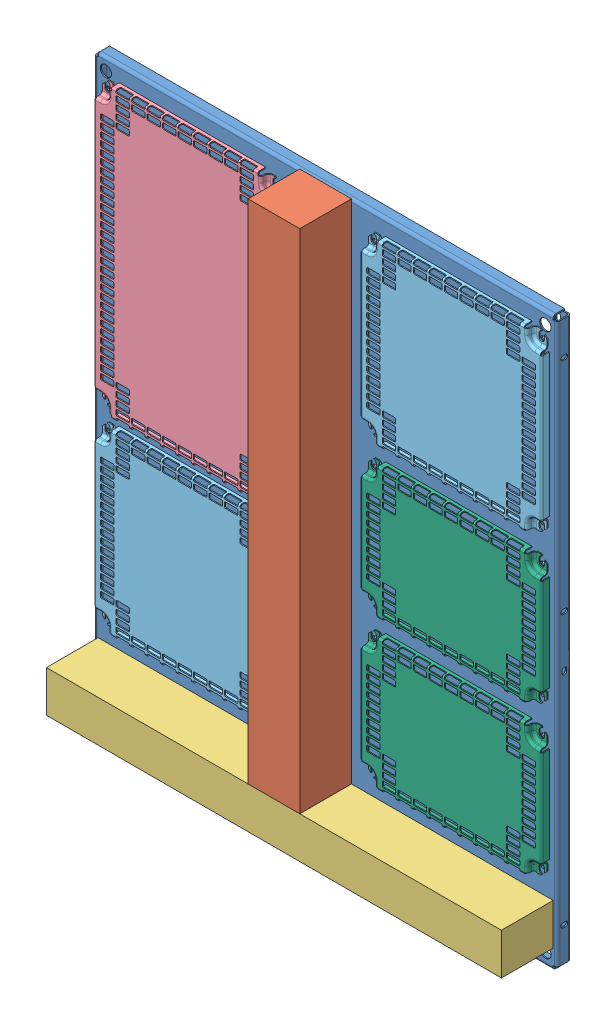
SolidWorks assembly Assemblage1, configuration Défaut. Lengths in mm.
Overall size (896 1097 127).
8 component instances, 6 part files, 21 mates.
Components (placement in the parent):
- Platine de fond -1: Platine de fond  [Défaut] at (-65.6964 -71.1067 1097) size (896 1097 27)
- goulotte 100x100-1: goulotte 100x100 [Défaut] at (-65.6964 -12.6067 1097) size (100 980 100)
- goulotte 80x100-1: goulotte 80x100 [Défaut] at (-65.6964 -542.6067 1097) x (0 -1 0) z (0 0 1) size (80 880 100)
- NSYMR64-1: NSYMR64 [Défaut] at (-323.1964 169.8933 1112) size (351 555 15.01)
- NSYMR44-1: NSYMR44 [Défaut] at (-323.1964 -300.1067 1112) size (351 345 15.02)
- NSYMR44-2: NSYMR44 [Défaut] at (191.8036 274.8933 1112) size (351 345 15.02)
- NSYMR34-1: NSYMR34 [Défaut] at (191.8036 -57.6067 1112) size (351 255 15.02)
- NSYMR34-2: NSYMR34 [Défaut] at (191.8036 -345.1067 1112) size (351 255 15.02)
Mates (geometry in assembly coordinates):
- Coïncidente1: coincident anti-aligned: plane of Platine de fond -1 through (-65.6964 -71.1067 1097) normal (0 0 1); plane of goulotte 100x100-1 through (-65.6964 -12.6067 1097) normal (0 0 -1)
- Coïncidente2: coincident aligned: plane of Platine de fond -1 through (-65.6964 477.3933 1097) normal (0 1 0); plane of goulotte 100x100-1 through (-115.6964 477.3933 1197) normal (0 1 0)
- Coïncidente3: coincident aligned: plane of Platine de fond -1 through (-65.6964 -71.1067 1097) normal (1 0 0); plane of goulotte 100x100-1 through (-65.6964 -12.6067 1097) normal (1 0 0)
- Coïncidente4: coincident anti-aligned: plane of goulotte 100x100-1 through (-115.6964 -502.6067 1197) normal (0 -1 0); plane of goulotte 80x100-1 through (374.3036 -502.6067 1197) normal (0 1 0)
- Coïncidente5: coincident anti-aligned: plane of Platine de fond -1 through (-65.6964 -71.1067 1097) normal (0 0 1); plane of goulotte 80x100-1 through (-65.6964 -542.6067 1097) normal (0 0 -1)
- Coïncidente6: coincident aligned: plane of goulotte 100x100-1 through (-65.6964 -12.6067 1097) normal (1 0 0); plane of goulotte 80x100-1
- Coïncidente7: coincident anti-aligned: plane of Platine de fond -1 through (-65.6964 -71.1067 1097) normal (0 0 1); plane of NSYMR64-1 through (-495.6964 442.3933 1097) normal (0 0 -1)
- Coïncidente8: coincident aligned: plane of NSYMR64-1 through (-323.1964 169.8933 1112) normal (0 0 1); plane of NSYMR44-1 through (-323.1964 -300.1067 1112) normal (0 0 1)
- Coïncidente9: coincident aligned: plane of NSYMR64-1 through (-498.6964 447.3933 1112) normal (-1 0 0); plane of NSYMR44-1 through (-498.6964 -127.6067 1112) normal (-1 0 0)
- Distance1: distance = 15 mm aligned: plane of NSYMR64-1 through (-498.6964 447.3933 1112) normal (-1 0 0); plane of Platine de fond -1 through (-513.6964 469.3557 1070) normal (-1 0 0)
- Coïncidente10: coincident aligned: plane of NSYMR64-1 through (-323.1964 169.8933 1112) normal (0 0 1); plane of NSYMR44-2 through (191.8036 274.8933 1112) normal (0 0 1)
- Coïncidente11: coincident aligned: plane of NSYMR64-1 through (-147.6964 447.3933 1112) normal (0 1 0); plane of NSYMR44-2 through (367.3036 447.3933 1112) normal (0 1 0)
- Distance2: distance = 15 mm aligned: plane of NSYMR44-2 through (367.3036 102.3933 1112) normal (1 0 0); plane of Platine de fond -1 through (382.3036 -611.5691 1070) normal (1 0 0)
- Coïncidente12: coincident aligned: plane of NSYMR34-1 through (191.8036 -57.6067 1112) normal (0 0 1); plane of NSYMR34-2 through (191.8036 -345.1067 1112) normal (0 0 1)
- Coïncidente13: coincident aligned: plane of NSYMR44-2 through (191.8036 274.8933 1112) normal (0 0 1); plane of NSYMR34-1 through (191.8036 -57.6067 1112) normal (0 0 1)
- Coïncidente14: coincident aligned: plane of NSYMR44-2 through (367.3036 102.3933 1112) normal (1 0 0); plane of NSYMR34-1 through (367.3036 -185.1067 1112) normal (1 0 0)
- Coïncidente15: coincident aligned: plane of NSYMR34-1 through (367.3036 -185.1067 1112) normal (1 0 0); plane of NSYMR34-2 through (367.3036 -472.6067 1112) normal (1 0 0)
- Coïncidente16: coincident aligned: plane of NSYMR44-1 through (-498.6964 -472.6067 1112) normal (0 -1 0); plane of NSYMR34-2 through (16.3036 -472.6067 1112) normal (0 -1 0)
- Distance3: distance = 30 mm aligned: plane of Platine de fond -1 through (-65.6964 477.3933 1097) normal (0 1 0); plane of NSYMR64-1 through (-147.6964 447.3933 1112) normal (0 1 0)
- Distance4: distance = 30 mm anti-aligned: plane of NSYMR44-1 through (-498.6964 -472.6067 1112) normal (0 -1 0); plane of goulotte 80x100-1 through (374.3036 -502.6067 1197) normal (0 1 0)
- Distance5: distance = 32.5 mm anti-aligned: plane of NSYMR34-1 through (367.3036 69.8933 1112) normal (0 1 0); plane of NSYMR44-2 through (16.3036 102.3933 1112) normal (0 -1 0)
